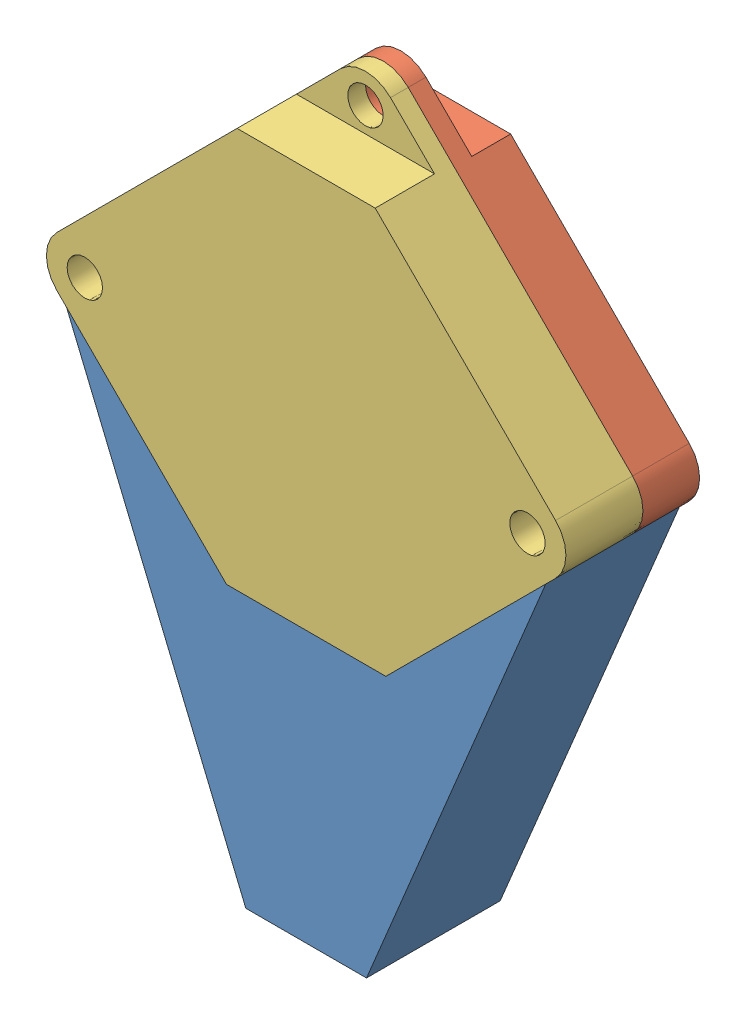
SolidWorks assembly earing assenb, configuration Default. Lengths in mm.
Overall size (29.34 47.74 9.12).
3 component instances, 3 part files, 5 mates.
Components (placement in the parent):
- glowpart-1: glowpart [Default] at (29.877 351.6808 173.2099) x (1 0 0) z (0 0.028433 0.999596) size (27.06 24.54 8.24)
- non battery cover-2: non battery cover [Default] at (29.7437 356.1173 169.429) size (29.34 25.67 3.57)
- battery section-2: battery section [Default] at (30.2917 354.8698 172.629) size (29.34 25.67 4.35)
Mates (geometry in assembly coordinates):
- Coincident50: coincident aligned: plane of non battery cover-2 through (44.3775 356.2841 172.629) normal (0.707107 0.707107 0); plane of battery section-2 through (45.7917 354.8698 176.979) normal (0.707107 0.707107 0)
- Coincident51: coincident aligned: plane of non battery cover-2 through (28.8775 368.9556 172.629) normal (-0.707107 0.707107 0); plane of battery section-2 through (30.2917 370.3698 176.979) normal (-0.707107 0.707107 0)
- Coincident57: coincident anti-aligned: line of glowpart-1 through (34.7917 343.8698 172.629) axis (-1 0 0); line of non battery cover-2 through (32.4742 343.8698 172.629) axis (1 0 0)
- Coincident58: coincident aligned: line of glowpart-1 through (34.7917 343.8698 172.629) axis (0.707107 0.707107 0); line of non battery cover-2 through (34.7917 343.8698 172.629) axis (0.707107 0.707107 0)
- Coincident60: coincident anti-aligned: plane of non battery cover-2 through (17.6201 354.8698 172.629) normal (0 0 1); plane of battery section-2 through (30.2917 354.8698 172.629) normal (0 0 -1)
